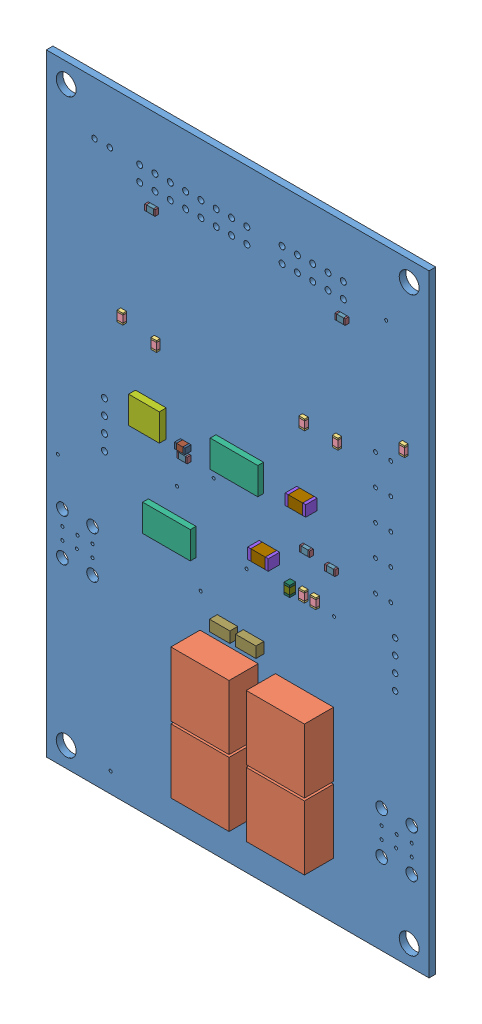
SolidWorks assembly Solar_10cell_S_PCB_4x2.5, configuration Default. Lengths in mm.
Overall size (63.5 101.6 11.03).
154 component instances, 16 part files, 0 mates.
Components (placement in the parent):
- Board-1: Board [Default] at (0 0 -1.1024) size (63.5 101.6 1.1)
- Q33-1: Q33 [Default] at origin size (9.65 10.65 4.83)
  - 544263024-1: 544263024 [Default] at (77.881 67.183 -5.9324) size (9.65 10.65 4.83)
    - Extruded-1: Extruded [Default] at origin size (9.65 10.65 4.83)
- Q32-1: Q32 [Default] at origin size (9.65 10.65 4.83)
  - 544263024-1: 544263024 [Default] at (65.375 67.183 -5.9324) size (9.65 10.65 4.83)
    - Extruded-1: Extruded [Default] at origin size (9.65 10.65 4.83)
- Q31-1: Q31 [Default] at origin size (9.65 10.65 4.83)
  - 544263024-1: 544263024 [Default] at (77.881 78.486 -5.9324) size (9.65 10.65 4.83)
    - Extruded-1: Extruded [Default] at origin size (9.65 10.65 4.83)
- Q30-1: Q30 [Default] at origin size (9.65 10.65 4.83)
  - 544263024-1: 544263024 [Default] at (65.375 78.486 -5.9324) size (9.65 10.65 4.83)
    - Extruded-1: Extruded [Default] at origin size (9.65 10.65 4.83)
- R84-1: R84 [Default] at origin size (0.95 1.7 0.6)
  - 544262896-1: 544262896 [Default] at (53.4671 127.3339 0) size (0.95 0.27 0.6)
    - Extruded_2-1: Extruded_2 [Default] at origin size (0.95 0.27 0.6)
  - 544262768-1: 544262768 [Default] at (53.4671 126.6189 0) size (0.95 1.16 0.6)
    - Extruded_3-1: Extruded_3 [Default] at origin size (0.95 1.16 0.6)
  - 544262896-2: 544262896 [Default] at (53.4671 125.9039 0) size (0.95 0.27 0.6)
    - Extruded_2-1: Extruded_2 [Default] at origin size (0.95 0.27 0.6)
- R82-1: R82 [Default] at origin size (0.95 1.7 0.6)
  - 544262896-1: 544262896 [Default] at (83.5661 128.3499 0) size (0.95 0.27 0.6)
    - Extruded_2-1: Extruded_2 [Default] at origin size (0.95 0.27 0.6)
  - 544262768-1: 544262768 [Default] at (83.5661 127.6349 0) size (0.95 1.16 0.6)
    - Extruded_3-1: Extruded_3 [Default] at origin size (0.95 1.16 0.6)
  - 544262896-2: 544262896 [Default] at (83.5661 126.9199 0) size (0.95 0.27 0.6)
    - Extruded_2-1: Extruded_2 [Default] at origin size (0.95 0.27 0.6)
- R10-1: R10 [Default] at origin size (0.95 1.7 0.6)
  - 544262896-1: 544262896 [Default] at (94.6149 132.7951 0) size (0.95 0.27 0.6)
    - Extruded_2-1: Extruded_2 [Default] at origin size (0.95 0.27 0.6)
  - 544262768-1: 544262768 [Default] at (94.6149 132.0801 0) size (0.95 1.16 0.6)
    - Extruded_3-1: Extruded_3 [Default] at origin size (0.95 1.16 0.6)
  - 544262896-2: 544262896 [Default] at (94.6149 131.3651 0) size (0.95 0.27 0.6)
    - Extruded_2-1: Extruded_2 [Default] at origin size (0.95 0.27 0.6)
- S5-1: S5 [Default] at origin size (6 10 5.08)
  - C-4-1437565-1-1: C-4-1437565-1 [Default] at (90.9319 141.7321 -4.7976) x (-1 0 0) z (0 0 -1) size (6 10 5.08)
- U1-1: U1 [Default] at origin size (7.9 4.5 0.95)
  - 549702320-1: 549702320 [Default] at (67.395 116.285 0.25) size (7.9 4.5 0.95)
    - Extruded_4-1: Extruded_4 [Default] at origin size (7.9 4.5 0.95)
- U3-1: U3 [Default] at origin size (5.1 4.5 1.15)
  - 549703728-1: 549703728 [Default] at (52.451 115.824 0.05) size (5.1 4.5 1.15)
    - Extruded_5-1: Extruded_5 [Default] at origin size (5.1 4.5 1.15)
- C35-1: C35 [Default] at origin size (3.4 1.8 1.9)
  - 549702576-1: 549702576 [Default] at (73.523 105.799 0) size (0.5 1.8 1.9)
    - Extruded_6-1: Extruded_6 [Default] at origin size (0.5 1.8 1.9)
  - 549702576-2: 549702576 [Default] at (70.623 105.799 0) size (0.5 1.8 1.9)
    - Extruded_6-1: Extruded_6 [Default] at origin size (0.5 1.8 1.9)
  - 549702448-1: 549702448 [Default] at (72.073 105.799 0) size (2.4 1.8 1.9)
    - Extruded_7-1: Extruded_7 [Default] at origin size (2.4 1.8 1.9)
- C33-1: C33 [Default] at origin size (1.75 0.95 1)
  - 544265712-1: 544265712 [Default] at (58.881 114.308 0) size (0.35 0.95 1)
    - Extruded_8-1: Extruded_8 [Default] at origin size (0.35 0.95 1)
  - 544265712-2: 544265712 [Default] at (57.481 114.308 0) size (0.35 0.95 1)
    - Extruded_8-1: Extruded_8 [Default] at origin size (0.35 0.95 1)
  - 544265584-1: 544265584 [Default] at (58.181 114.308 0) size (1.05 0.95 1)
    - Extruded_9-1: Extruded_9 [Default] at origin size (1.05 0.95 1)
- U2-1: U2 [Default] at origin size (7.9 4.5 0.95)
  - 549702320-1: 549702320 [Default] at (56.187 101.473 0.25) size (7.9 4.5 0.95)
    - Extruded_4-1: Extruded_4 [Default] at origin size (7.9 4.5 0.95)
- C30-1: C30 [Default] at origin size (3.4 1.8 1.3)
  - 544265968-1: 544265968 [Default] at (69.43 91.651 0) size (3.4 1.8 1.3)
    - Extruded_10-1: Extruded_10 [Default] at origin size (3.4 1.8 1.3)
- C29-1: C29 [Default] at origin size (3.4 1.8 1.3)
  - 544265968-1: 544265968 [Default] at (65.112 91.651 0) size (3.4 1.8 1.3)
    - Extruded_10-1: Extruded_10 [Default] at origin size (3.4 1.8 1.3)
- Q20-1: Q20 [Default] at origin size (9.65 10.65 4.83)
  - 544263024-1: 544263024 [Default] at (77.881 72.517 0) size (9.65 10.65 4.83)
    - Extruded-1: Extruded [Default] at origin size (9.65 10.65 4.83)
- Q19-1: Q19 [Default] at origin size (9.65 10.65 4.83)
  - 544263024-1: 544263024 [Default] at (65.375 72.517 0) size (9.65 10.65 4.83)
    - Extruded-1: Extruded [Default] at origin size (9.65 10.65 4.83)
- Q18-1: Q18 [Default] at origin size (9.65 10.65 4.83)
  - 544263024-1: 544263024 [Default] at (77.881 83.566 0) size (9.65 10.65 4.83)
    - Extruded-1: Extruded [Default] at origin size (9.65 10.65 4.83)
- Q17-1: Q17 [Default] at origin size (9.65 10.65 4.83)
  - 544263024-1: 544263024 [Default] at (65.375 83.566 0) size (9.65 10.65 4.83)
    - Extruded-1: Extruded [Default] at origin size (9.65 10.65 4.83)
- R63-1: R63 [Default] at origin size (1.7 0.95 0.6)
  - 544261232-1: 544261232 [Default] at (77.7861 109.4821 0) size (0.27 0.95 0.6)
    - Extruded_11-1: Extruded_11 [Default] at origin size (0.27 0.95 0.6)
  - 544261488-1: 544261488 [Default] at (78.5011 109.4821 0) size (1.16 0.95 0.6)
    - Extruded_12-1: Extruded_12 [Default] at origin size (1.16 0.95 0.6)
  - 544261232-2: 544261232 [Default] at (79.2161 109.4821 0) size (0.27 0.95 0.6)
    - Extruded_11-1: Extruded_11 [Default] at origin size (0.27 0.95 0.6)
- R51-1: R51 [Default] at origin size (1.7 0.95 0.6)
  - 544261232-1: 544261232 [Default] at (81.9619 108.8389 0) size (0.27 0.95 0.6)
    - Extruded_11-1: Extruded_11 [Default] at origin size (0.27 0.95 0.6)
  - 544261488-1: 544261488 [Default] at (82.6769 108.8389 0) size (1.16 0.95 0.6)
    - Extruded_12-1: Extruded_12 [Default] at origin size (1.16 0.95 0.6)
  - 544261232-2: 544261232 [Default] at (83.3919 108.8389 0) size (0.27 0.95 0.6)
    - Extruded_11-1: Extruded_11 [Default] at origin size (0.27 0.95 0.6)
- R85-1: R85 [Default] at origin size (0.95 1.7 0.6)
  - 544262896-1: 544262896 [Default] at (47.8791 127.0469 0) size (0.95 0.27 0.6)
    - Extruded_2-1: Extruded_2 [Default] at origin size (0.95 0.27 0.6)
  - 544262768-1: 544262768 [Default] at (47.8791 127.7619 0) size (0.95 1.16 0.6)
    - Extruded_3-1: Extruded_3 [Default] at origin size (0.95 1.16 0.6)
  - 544262896-2: 544262896 [Default] at (47.8791 128.4769 0) size (0.95 0.27 0.6)
    - Extruded_2-1: Extruded_2 [Default] at origin size (0.95 0.27 0.6)
- R83-1: R83 [Default] at origin size (0.95 1.7 0.6)
  - 544262896-1: 544262896 [Default] at (78.0411 126.9279 0) size (0.95 0.27 0.6)
    - Extruded_2-1: Extruded_2 [Default] at origin size (0.95 0.27 0.6)
  - 544262768-1: 544262768 [Default] at (78.0411 127.6429 0) size (0.95 1.16 0.6)
    - Extruded_3-1: Extruded_3 [Default] at origin size (0.95 1.16 0.6)
  - 544262896-2: 544262896 [Default] at (78.0411 128.3579 0) size (0.95 0.27 0.6)
    - Extruded_2-1: Extruded_2 [Default] at origin size (0.95 0.27 0.6)
- R62-1: R62 [Default] at origin size (0.95 1.7 0.6)
  - 544262896-1: 544262896 [Default] at (77.9931 103.5929 0) size (0.95 0.27 0.6)
    - Extruded_2-1: Extruded_2 [Default] at origin size (0.95 0.27 0.6)
  - 544262768-1: 544262768 [Default] at (77.9931 102.8779 0) size (0.95 1.16 0.6)
    - Extruded_3-1: Extruded_3 [Default] at origin size (0.95 1.16 0.6)
  - 544262896-2: 544262896 [Default] at (77.9931 102.1629 0) size (0.95 0.27 0.6)
    - Extruded_2-1: Extruded_2 [Default] at origin size (0.95 0.27 0.6)
- R55-1: R55 [Default] at origin size (0.95 1.7 0.6)
  - 544262896-1: 544262896 [Default] at (79.8979 102.1631 0) size (0.95 0.27 0.6)
    - Extruded_2-1: Extruded_2 [Default] at origin size (0.95 0.27 0.6)
  - 544262768-1: 544262768 [Default] at (79.8979 102.8781 0) size (0.95 1.16 0.6)
    - Extruded_3-1: Extruded_3 [Default] at origin size (0.95 1.16 0.6)
  - 544262896-2: 544262896 [Default] at (79.8979 103.5931 0) size (0.95 0.27 0.6)
    - Extruded_2-1: Extruded_2 [Default] at origin size (0.95 0.27 0.6)
- C26-1: C26 [Default] at origin size (0.95 1.75 1)
  - 544263536-1: 544263536 [Default] at (75.961 102.178 0) size (0.95 0.35 1)
    - Extruded_13-1: Extruded_13 [Default] at origin size (0.95 0.35 1)
  - 544263536-2: 544263536 [Default] at (75.961 103.578 0) size (0.95 0.35 1)
    - Extruded_13-1: Extruded_13 [Default] at origin size (0.95 0.35 1)
  - 544263664-1: 544263664 [Default] at (75.961 102.878 0) size (0.95 1.05 1)
    - Extruded_14-1: Extruded_14 [Default] at origin size (0.95 1.05 1)
- C32-1: C32 [Default] at origin size (3.4 1.8 1.9)
  - 549702576-1: 549702576 [Default] at (76.837 116.673 0) size (0.5 1.8 1.9)
    - Extruded_6-1: Extruded_6 [Default] at origin size (0.5 1.8 1.9)
  - 549702576-2: 549702576 [Default] at (79.737 116.673 0) size (0.5 1.8 1.9)
    - Extruded_6-1: Extruded_6 [Default] at origin size (0.5 1.8 1.9)
  - 549702448-1: 549702448 [Default] at (78.287 116.673 0) size (2.4 1.8 1.9)
    - Extruded_7-1: Extruded_7 [Default] at origin size (2.4 1.8 1.9)
- R89-1: R89 [Default] at origin size (1.7 0.95 0.6)
  - 544261232-1: 544261232 [Default] at (57.4661 112.7841 0) size (0.27 0.95 0.6)
    - Extruded_11-1: Extruded_11 [Default] at origin size (0.27 0.95 0.6)
  - 544261488-1: 544261488 [Default] at (58.1811 112.7841 0) size (1.16 0.95 0.6)
    - Extruded_12-1: Extruded_12 [Default] at origin size (1.16 0.95 0.6)
  - 544261232-2: 544261232 [Default] at (58.8961 112.7841 0) size (0.27 0.95 0.6)
    - Extruded_11-1: Extruded_11 [Default] at origin size (0.27 0.95 0.6)
- R93-1: R93 [Default] at origin size (1.7 0.95 0.6)
  - 544261232-1: 544261232 [Default] at (83.6719 145.7729 0) size (0.27 0.95 0.6)
    - Extruded_11-1: Extruded_11 [Default] at origin size (0.27 0.95 0.6)
  - 544261488-1: 544261488 [Default] at (84.3869 145.7729 0) size (1.16 0.95 0.6)
    - Extruded_12-1: Extruded_12 [Default] at origin size (1.16 0.95 0.6)
  - 544261232-2: 544261232 [Default] at (85.1019 145.7729 0) size (0.27 0.95 0.6)
    - Extruded_11-1: Extruded_11 [Default] at origin size (0.27 0.95 0.6)
- R95-1: R95 [Default] at origin size (1.7 0.95 0.6)
  - 544261232-1: 544261232 [Default] at (52.1169 145.6689 0) size (0.27 0.95 0.6)
    - Extruded_11-1: Extruded_11 [Default] at origin size (0.27 0.95 0.6)
  - 544261488-1: 544261488 [Default] at (52.8319 145.6689 0) size (1.16 0.95 0.6)
    - Extruded_12-1: Extruded_12 [Default] at origin size (1.16 0.95 0.6)
  - 544261232-2: 544261232 [Default] at (53.5469 145.6689 0) size (0.27 0.95 0.6)
    - Extruded_11-1: Extruded_11 [Default] at origin size (0.27 0.95 0.6)
